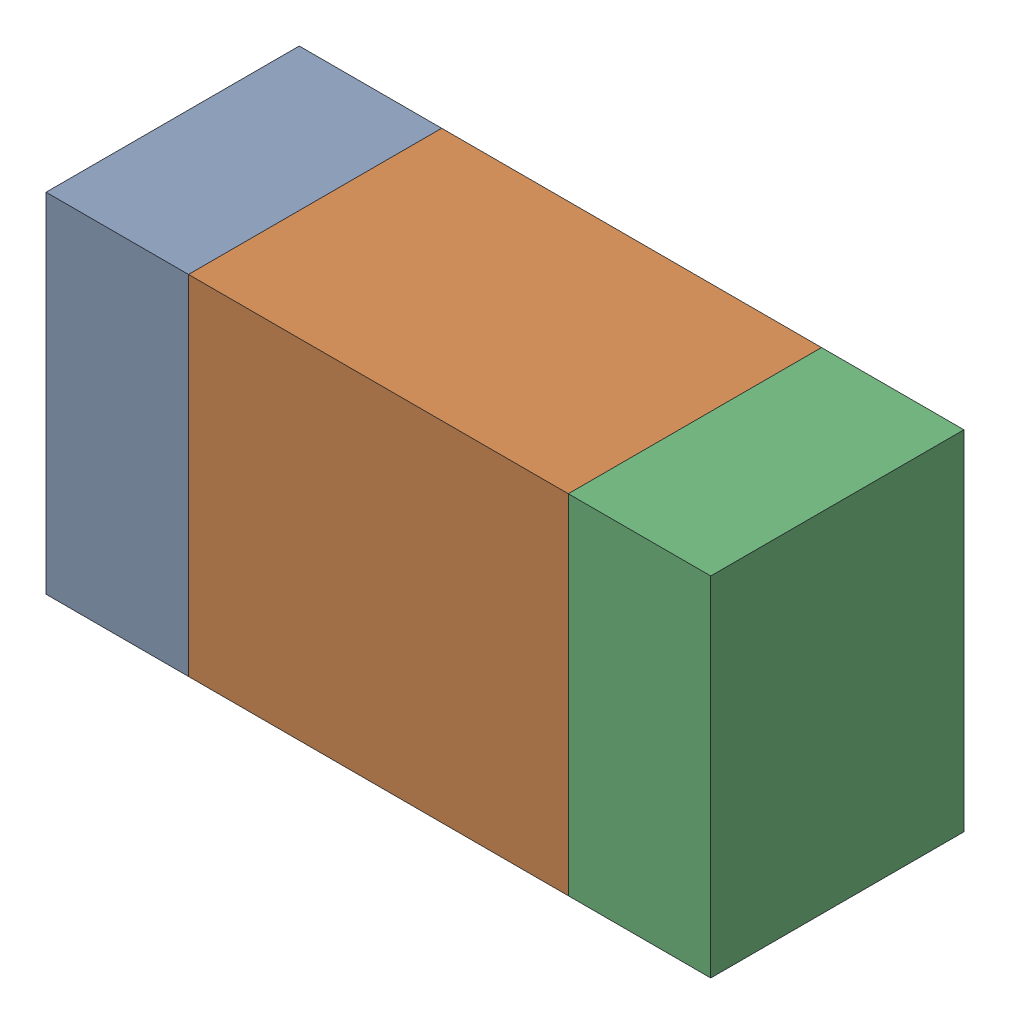
SolidWorks assembly R414PCB, configuration Default. Lengths in mm.
Overall size (1.05 0.55 0.4).
6 component instances, 2 part files, 0 mates.
Components (placement in the parent):
- 854785432-1: 854785432 [Default] at (122.5876 102.1999 -2.0638) size (0.22 0.55 0.4)
  - Extruded-1: Extruded [Default] at origin size (0.22 0.55 0.4)
- 854785568-1: 854785568 [Default] at (123.0001 102.1999 -2.0638) size (0.6 0.55 0.4)
  - Extruded_2-1: Extruded_2 [Default] at origin size (0.6 0.55 0.4)
- 854785432-2: 854785432 [Default] at (123.4126 102.1999 -2.0638) size (0.22 0.55 0.4)
  - Extruded-1: Extruded [Default] at origin size (0.22 0.55 0.4)
